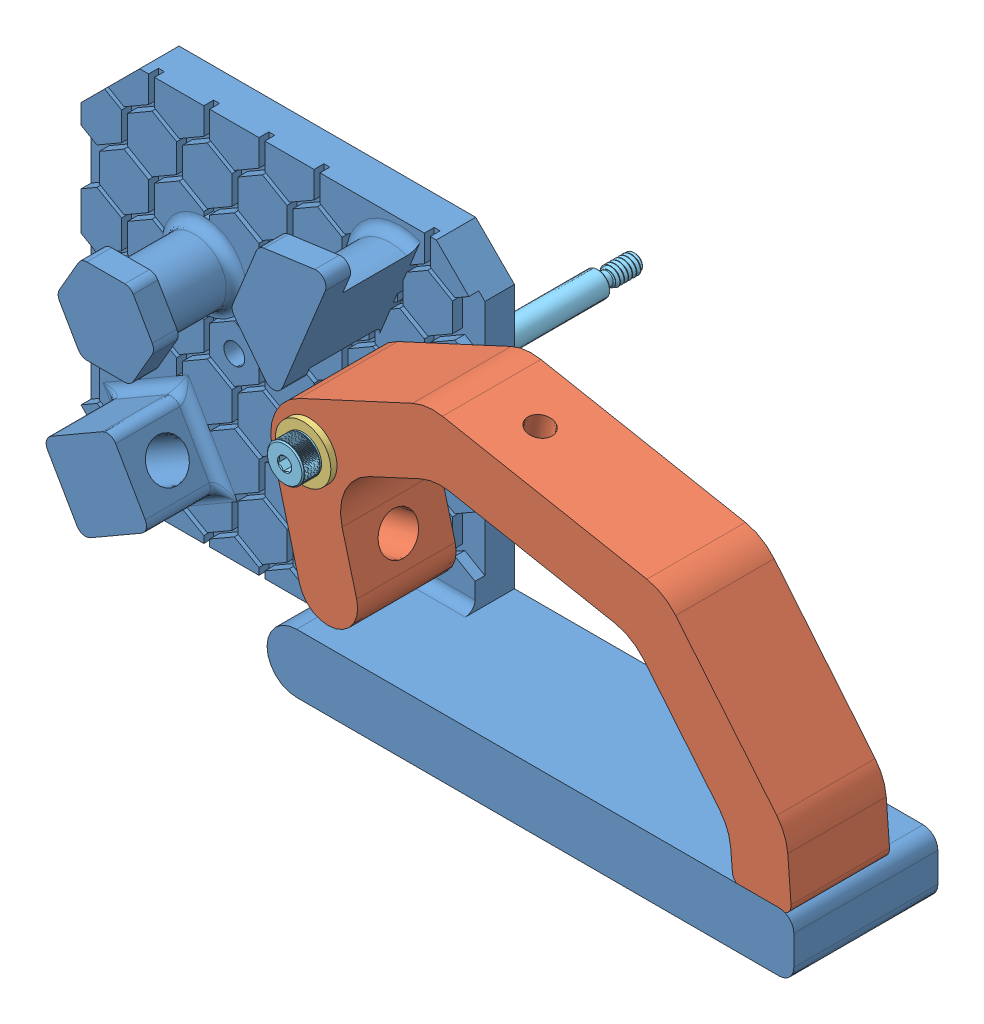
SolidWorks assembly MS-A-0013c-Gripper Hand, configuration Default. Lengths in mm.
Overall size (217.31 157.41 91.11).
6 component instances, 5 part files, 10 mates.
Components (placement in the parent):
- MS-P-0051-Gripper Hand Back Panel-1: MS-P-0051-Gripper Hand Back Panel [Default] at (-64.4091 18.8681 157.7425) x (0 0 1) z (-1 0 0) size (37.15 100.98 210.82)
- MS-P-0053-Gripper Hand Moving Finger-1: MS-P-0053-Gripper Hand Moving Finger [Default] at (18.1539 81.8882 159.33) x (0 0 1) z (-0.617261 0.786759 0) size (25.4 103.48 118.89)
- 6389K406_LIGHT DUTY DRY-RUNNING SLEEVE BEARING-1: 6389K406_LIGHT DUTY DRY-RUNNING SLEEVE BEARING [6389K406] at (21.4092 80.3575 186.3175) x (-0.260924 -0.965359 0) z (0.965359 -0.260924 0) size (14.29 12.7 14.29)
- 6389K406_LIGHT DUTY DRY-RUNNING SLEEVE BEARING-3: 6389K406_LIGHT DUTY DRY-RUNNING SLEEVE BEARING [6389K406] at (21.4092 80.3575 157.7425) x (-0.142341 0.989818 0) z (0.989818 0.142341 0) size (14.29 12.7 14.29)
- 91831A029_TYPE 18-8 STAINLESS STL NYLON-INSERT LOCKNUT-1: 91831A029_TYPE 18-8 STAINLESS STL NYLON-INSERT LOCKNUT [91831A029] at (21.4092 80.3575 147.5825) x (0.82514 -0.564929 0) z (0.564929 0.82514 0) size (11.11 8.13 12.83)
- 90298A552_18-8 STAINLESS STEEL SHOULDER SCREW-1: 90298A552_18-8 STAINLESS STEEL SHOULDER SCREW [90298A552] at (21.4092 80.3575 191.08) x (0.30218 -0.953251 0) z (0 0 1) size (9.53 9.53 91.11)
Mates (geometry in assembly coordinates):
- Coincident46: coincident anti-aligned: plane of MovingClaw-1 through (26.2731 51.1939 159.33) normal (0 0 -1); plane of 6389K406_LIGHT DUTY DRY-RUNNING SLEEVE BEARING-3 through (21.4092 80.3575 159.33) normal (0 0 1)
- Coincident49: coincident anti-aligned: plane of MovingClaw-1 through (26.2731 51.1939 184.73) normal (0 0 1); plane of 6389K406_LIGHT DUTY DRY-RUNNING SLEEVE BEARING-1 through (21.4092 80.3575 184.73) normal (0 0 -1)
- Coincident54: coincident aligned: plane of BackPanel-1 through (-64.4091 18.8681 157.7425) normal (0 0 1); circle of 6389K406_LIGHT DUTY DRY-RUNNING SLEEVE BEARING-3
- Concentric19: concentric anti-aligned: circle of 6389K406_LIGHT DUTY DRY-RUNNING SLEEVE BEARING-1; circle of 91259A546_ALLOY STEEL SHOULDER SCREW-1
- Coincident28: coincident aligned: circle of 6389K406_LIGHT DUTY DRY-RUNNING SLEEVE BEARING-1; plane of 91259A546_ALLOY STEEL SHOULDER SCREW-1 through (16.8694 78.9184 186.3175) normal (0 0 -1)
- Concentric20: concentric anti-aligned: circle of 6389K406_LIGHT DUTY DRY-RUNNING SLEEVE BEARING-1; circle of 6389K406_LIGHT DUTY DRY-RUNNING SLEEVE BEARING-3
- Concentric21: concentric anti-aligned: circle of MovingClaw-1; circle of 6389K406_LIGHT DUTY DRY-RUNNING SLEEVE BEARING-1
- Concentric22: concentric aligned: circle of BackPanel-1; circle of 91259A546_ALLOY STEEL SHOULDER SCREW-1
- Concentric23: concentric aligned: circle of 91831A029_TYPE 18-8 STAINLESS STL NYLON-INSERT LOCKNUT-1; circle of 91259A546_ALLOY STEEL SHOULDER SCREW-1
- Coincident57: coincident anti-aligned: plane of BackPanel-1 through (-64.4091 18.8681 147.5825) normal (0 0 -1); plane of 91831A029_TYPE 18-8 STAINLESS STL NYLON-INSERT LOCKNUT-1 through (11.3878 75.5555 147.5825) normal (0 0 1)
